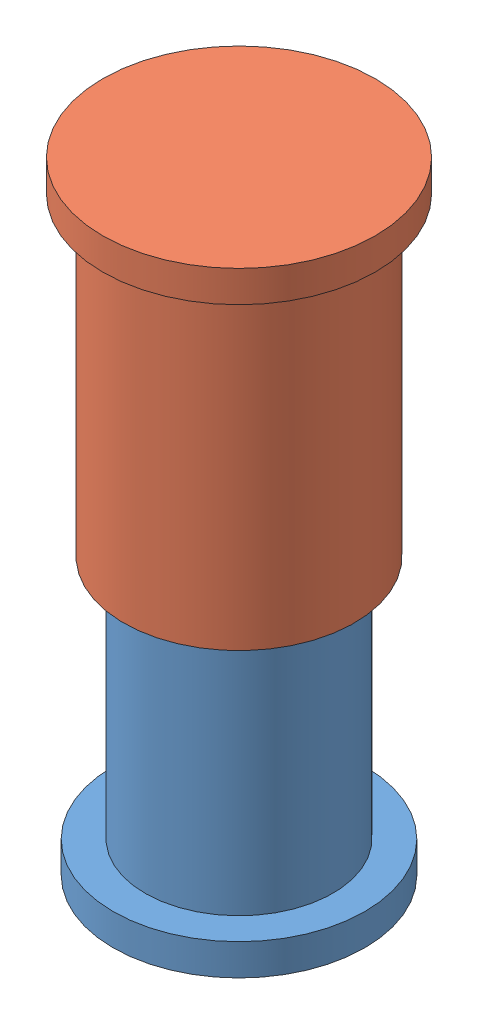
SolidWorks assembly Assem1, configuration Default. Lengths in mm.
Overall size (168.35 296.74 168.35).
3 component instances, 3 part files, 3 mates.
Components (placement in the parent):
- Base-1: Base [Default] at origin size (200 40 150) (hidden)
- male_damper-1: male_damper [Default] at (0 190 0) x (0.612325 0 -0.790606) z (-0.790606 0 -0.612325) size (120 165 120)
- Female_damper-1: Female_damper [Default] at (0 306.738 0) x (0.2565 0 0.966544) z (0.966544 0 -0.2565) size (130 165 130)
Mates (geometry in assembly coordinates):
- Concentric1: concentric aligned: cylinder of Base-1 through (0 25 0) axis (0 1 0) radius 60; cylinder of male_damper-1 through (0 25 0) axis (0 1 0) radius 60
- Coincident1: coincident anti-aligned: circle of Base-1; circle of male_damper-1
- Concentric2: concentric aligned: cylinder of male_damper-1 through (0 40 0) axis (0 1 0) radius 44.85; cylinder of Female_damper-1 through (0 156.738 0) axis (0 1 0) radius 45.05
